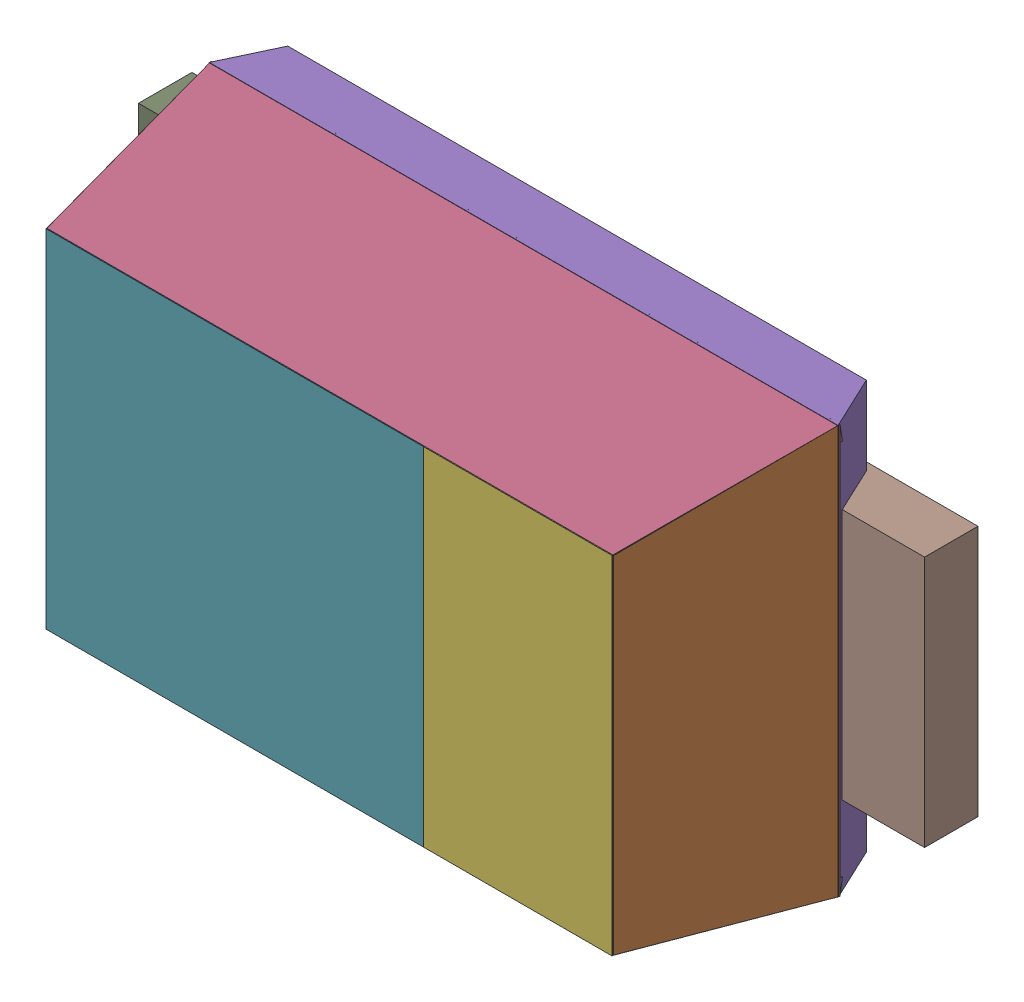
SolidWorks assembly User Library-Arduino Nano 3.0_User Library-TUMD2, configuration Default. Lengths in mm.
Overall size (2.5 1.3 0.81).
19 component instances, 7 part files, 0 mates.
Components (placement in the parent):
- User Library-Arduino Nano 3.0_User Library-TUMD2_Free-Models-1: User Library-Arduino Nano 3.0_User Library-TUMD2_Free-Models [Default] at origin size (2.5 1.3 0.81)
  - User Library-Arduino Nano 3.0_User Library-TUMD2_BODY_L-1: User Library-Arduino Nano 3.0_User Library-TUMD2_BODY_L [Default] at (1.08 -0.6007 0.5) x (-1 0 0) z (0 0.987688 -0.156434) size (2 0.63 0.05)
    - User Library-Arduino Nano 3.0_User Library-TUMD2_Extruded-1: User Library-Arduino Nano 3.0_User Library-TUMD2_Extruded [Default] at origin size (2 0.63 0.05)
  - User Library-Arduino Nano 3.0_User Library-TUMD2_BODY_S-1: User Library-Arduino Nano 3.0_User Library-TUMD2_BODY_S [Default] at (2.0307 0 0.5) x (0.156434 0 -0.987688) z (-0.987688 0 -0.156434) size (0.63 1.3 0.05)
    - User Library-Arduino Nano 3.0_User Library-TUMD2_Extruded_2-1: User Library-Arduino Nano 3.0_User Library-TUMD2_Extruded_2 [Default] at origin size (0.63 1.3 0.05)
  - User Library-Arduino Nano 3.0_User Library-TUMD2_BODY_S-2: User Library-Arduino Nano 3.0_User Library-TUMD2_BODY_S [Default] at (0.1293 0 0.5) x (-0.156434 0 -0.987688) z (0.987688 0 -0.156434) size (0.63 1.3 0.05)
    - User Library-Arduino Nano 3.0_User Library-TUMD2_Extruded_2-1: User Library-Arduino Nano 3.0_User Library-TUMD2_Extruded_2 [Default] at origin size (0.63 1.3 0.05)
  - User Library-Arduino Nano 3.0_User Library-TUMD2_BODY_L-2: User Library-Arduino Nano 3.0_User Library-TUMD2_BODY_L [Default] at (1.08 0.6007 0.5) x (1 0 0) z (0 -0.987688 -0.156434) size (2 0.63 0.05)
    - User Library-Arduino Nano 3.0_User Library-TUMD2_Extruded-1: User Library-Arduino Nano 3.0_User Library-TUMD2_Extruded [Default] at origin size (2 0.63 0.05)
  - User Library-Arduino Nano 3.0_User Library-TUMD2_BASE-1: User Library-Arduino Nano 3.0_User Library-TUMD2_BASE [Default] at (1.08 0.65 0.11) x (1 0 0) z (0 -1 0) size (2 0.17 1.3)
    - User Library-Arduino Nano 3.0_User Library-TUMD2_Extruded_3-1: User Library-Arduino Nano 3.0_User Library-TUMD2_Extruded_3 [Default] at origin size (2 0.17 1.3)
  - User Library-Arduino Nano 3.0_User Library-TUMD2_702825728-1: User Library-Arduino Nano 3.0_User Library-TUMD2_702825728 [Default] at (1.68 0 0.75) size (0.6 1.1 0.06)
    - User Library-Arduino Nano 3.0_User Library-TUMD2_Extruded_4-1: User Library-Arduino Nano 3.0_User Library-TUMD2_Extruded_4 [Default] at origin size (0.6 1.1 0.06)
  - User Library-Arduino Nano 3.0_User Library-TUMD2_702828800-1: User Library-Arduino Nano 3.0_User Library-TUMD2_702828800 [Default] at (0.78 0 0.75) size (1.2 1.1 0.06)
    - User Library-Arduino Nano 3.0_User Library-TUMD2_Extruded_5-1: User Library-Arduino Nano 3.0_User Library-TUMD2_Extruded_5 [Default] at origin size (1.2 1.1 0.06)
  - User Library-Arduino Nano 3.0_User Library-TUMD2_675155360-1: User Library-Arduino Nano 3.0_User Library-TUMD2_675155360 [Default] at (1.58 0 0) size (1.5 0.8 0.17)
    - User Library-Arduino Nano 3.0_User Library-TUMD2_Extruded_6-1: User Library-Arduino Nano 3.0_User Library-TUMD2_Extruded_6 [Default] at origin size (1.5 0.8 0.17)
  - User Library-Arduino Nano 3.0_User Library-TUMD2_676056384-1: User Library-Arduino Nano 3.0_User Library-TUMD2_676056384 [Default] at (0.005 0 0) size (0.35 0.8 0.17)
    - User Library-Arduino Nano 3.0_User Library-TUMD2_Extruded_7-1: User Library-Arduino Nano 3.0_User Library-TUMD2_Extruded_7 [Default] at origin size (0.35 0.8 0.17)
